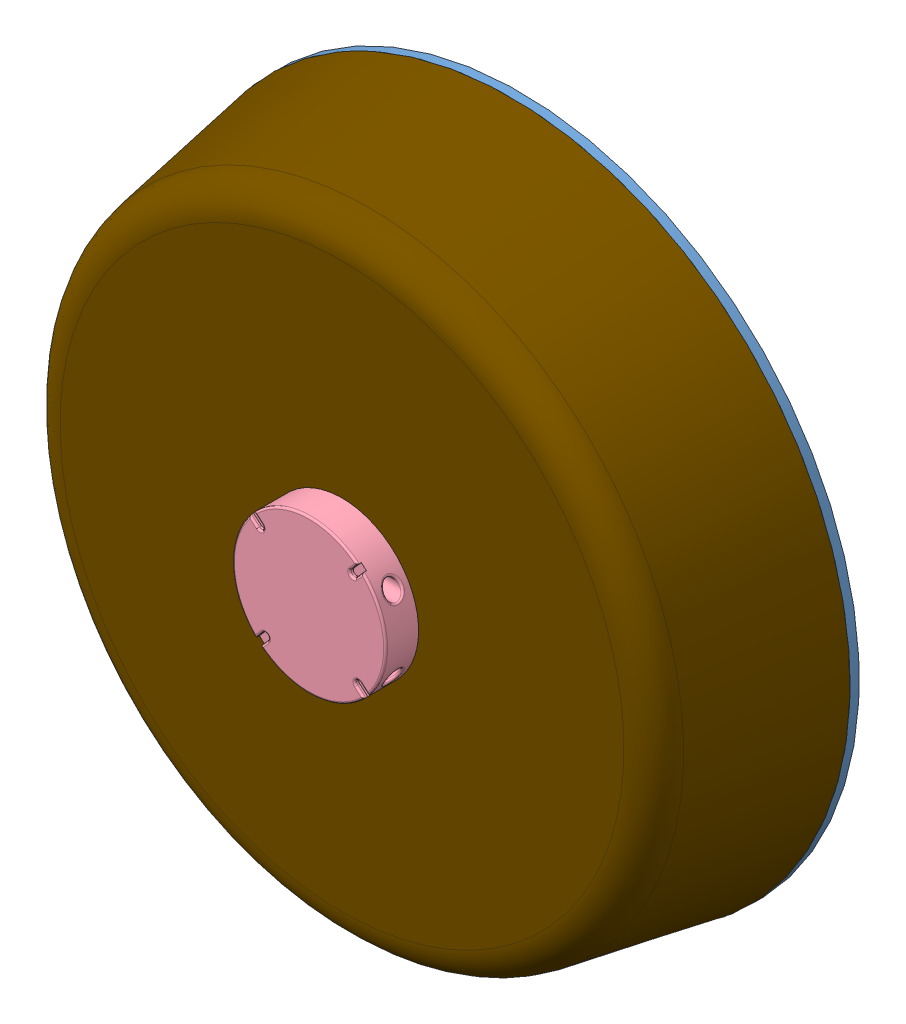
SolidWorks assembly Assembly, configuration Default. Lengths in mm.
Overall size (471.24 471.24 136.97).
49 component instances, 23 part files, 116 mates.
Components (placement in the parent):
- base 4.75mm MDF-1: base 4.75mm MDF [Default] at (205.0733 190.9358 207.8318) size (350 350 4.75)
- caster rise-1: caster rise [Default] at (335.0733 220.9358 207.8318) x (-1 0 0) z (0 1 0) size (60 32 4.75)
- caster rise-2: caster rise [Default] at (275.0733 160.9358 207.8318) x (1 0 0) z (0 -1 0) size (60 32 4.75)
- caster attatchment plate-1: caster attatchment plate [Default] at (305.0733 190.9358 230.0818) size (60 69.5 4.75)
- motor side mdf-1: motor side mdf [Default] at (270.0733 296.9358 212.5818) x (-1 0 0) z (0 1 0) size (115.32 83 4.75)
- motor side mdf-2: motor side mdf [Default] at (270.0733 80.1858 212.5818) x (-1 0 0) z (0 1 0) size (115.32 83 4.75)
- outside side mdf-1: outside side mdf [Default] at (270.0733 330.9358 212.5818) x (-1 0 0) z (0 1 0) size (115.32 83 4.75)
- inside side base-3: inside side base [Default] at (165.0733 330.9358 212.5818) size (95 23 4.75)
- inside side base-4: inside side base [Default] at (165.0733 50.9358 217.3318) x (1 0 0) z (0 0 -1) size (95 23 4.75)
- outside side mdf-2: outside side mdf [Default] at (270.0733 46.1858 212.5818) x (-1 0 0) z (0 1 0) size (115.32 83 4.75)
- wheel cover-1: wheel cover [Default] at (285.0733 330.9358 212.5818) x (-1 0 0) z (0 1 0) size (119.84 83 29.25)
- wheel cover-2: wheel cover [Default] at (285.0733 80.1858 212.5818) x (-1 0 0) z (0 1 0) size (119.84 83 29.25)
- Arm mdf model-1: Arm mdf model [Default] at (210.848 314.4358 240.6942) x (0.799121 0 -0.60117) z (0 -1 0) size (25 92.5 36.95)
- Arm mdf model-2: Arm mdf model [Default] at (218.8392 69.2358 234.6825) x (-0.799121 0 0.60117) z (0 1 0) size (25 92.5 36.95)
- wheel-1: wheel [Default] at (207.9564 56.4358 228.5333) x (0.99189 0 0.127103) z (0 1 0) size (70 70 9)
- wheel-2: wheel [Default] at (207.9564 325.4358 228.5333) x (-0.581743 0 0.813373) z (0 -1 0) size (70 70 9)
- 3mm pin cavity-2: 3mm pin cavity [Default] at (277.411 65.5608 197.5818) size (3 3 20) (hidden)
- 3mm pin cavity-4: 3mm pin cavity [Default] at (277.411 316.3108 197.5818) size (3 3 20) (hidden)
- arm rod block-1: arm rod block [Default] at (225.5649 41.4358 277.495) x (1 0 0) z (0 1 0) size (15 15 4.75)
- arm rod block-2: arm rod block [Default] at (183.4988 89.6858 262.2969) x (1 0 0) z (0 -1 0) size (15 15 4.75)
- arm rod block-3: arm rod block [Default] at (228.2215 292.1858 278.3933) x (1 0 0) z (0 1 0) size (15 15 4.75)
- arm rod block-4: arm rod block [Default] at (229.3289 340.4358 265.9607) x (1 0 0) z (0 -1 0) size (15 15 4.75)
- motor side supports mdf-5: motor side supports mdf [Default] at (169.8233 296.9358 217.3318) x (0 -1 0) z (-1 0 0) size (23 24.75 4.75)
- motor side supports mdf-6: motor side supports mdf [Default] at (260.0733 296.9358 217.3318) x (0 -1 0) z (-1 0 0) size (23 24.75 4.75)
- motor side supports mdf-7: motor side supports mdf [Default] at (165.0733 335.6858 217.3318) x (0 1 0) z (1 0 0) size (23 24.75 4.75)
- motor side supports mdf-8: motor side supports mdf [Default] at (255.3233 335.6858 217.3318) x (0 1 0) z (1 0 0) size (23 24.75 4.75)
- inside side base parts-1: inside side base parts [Default] at (260.0733 80.1858 212.5818) x (-1 0 0) z (0 0 1) size (20 23 4.75)
- inside side base parts-3: inside side base parts [Default] at (165.0733 80.1858 217.3318) x (1 0 0) z (0 0 -1) size (20 23 4.75)
- motor side supports mdf-9: motor side supports mdf [Default] at (165.0733 84.9358 217.3318) x (0 1 0) z (1 0 0) size (23 24.75 4.75)
- motor side supports mdf-10: motor side supports mdf [Default] at (255.3233 84.9358 217.3318) x (0 1 0) z (1 0 0) size (23 24.75 4.75)
- motor side supports mdf-11: motor side supports mdf [Default] at (169.8233 46.1858 217.3318) x (0 -1 0) z (-1 0 0) size (23 24.75 4.75)
- motor side supports mdf-12: motor side supports mdf [Default] at (260.0733 46.1858 217.3318) x (0 -1 0) z (-1 0 0) size (23 24.75 4.75)
- inside side base parts-4: inside side base parts [Default] at (260.0733 301.6858 217.3318) x (-1 0 0) z (0 0 -1) size (20 23 4.75)
- inside side base parts-5: inside side base parts [Default] at (165.0733 301.6858 212.5818) size (20 23 4.75)
- 3mm pin cavity-5: 3mm pin cavity [Default] at (261.6585 38.9358 265.4258) x (1 0 0) z (0 1 0) size (3 3 20) (hidden)
- 3mm pin cavity-6: 3mm pin cavity [Default] at (261.6585 70.2183 265.4258) x (0.998958 0 -0.04563) z (0 1 0) size (3 3 20) (hidden)
- 25d-metal-gearmotor-75-99-encoder.step-1: 25d-metal-gearmotor-75-99-encoder.step [Default] at (207.9564 70.8358 228.5333) x (-0.811037 0 -0.584995) z (0 -1 0) size (25 30.75 80.95)
- 25d-metal-gearmotor-75-99-encoder.step-2: 25d-metal-gearmotor-75-99-encoder.step [Default] at (207.9564 312.8358 228.5333) x (0.533758 0 -0.845638) z (0 1 0) size (25 30.75 80.95)
- distance sensor-1: distance sensor [Default] at (370.0733 213.4358 222.1818) x (0 -1 0) z (1 0 0) size (45 15.6 20)
- vacuum area-1: vacuum area [Default] at (247.5733 190.9358 232.5818) x (0 1 0) z (0 0 -1) size (209.33 123.21 63.23)
- Battery holder v2-1: Battery holder v2 [Default] at (157.4034 248.4358 231.5818) x (0 -1 0) z (0 0 -1) size (125 51 24)
- dust bin-1: dust bin [Default] at (210.0733 190.9358 212.5818) x (0 0 1) z (0 1 0) size (86.03 115 321.71)
- case-1: case [Default] at (205.0733 190.9358 212.5818) x (-0.889778 -0.456394 0) z (-0.456394 0.889778 0) size (350.06 87 350.06)
- caster-1: caster [Default] at (305.0733 190.9358 230.0818) x (-1 0 0) z (0 0 -1) size (40 30 35.5)
- spring-1: spring [Default] at (183.9288 70.7358 291.8887) x (0.049441 0 0.998777) z (0 1 0) size (6.1 79.2 5.8)
- spring-2: spring [Default] at (243.8514 312.9358 288.8336) x (0.03981 0 0.999207) z (0 -1 0) size (6.1 79.2 5.8)
- XV11-main-1: XV11-main [Default] at (195.3613 245.7963 277.4612) x (0 1 0) z (1 0 0) size (99.25 29.09 118.97)
  - base-plate-1: base-plate [Default] at (-54.8605 13.6206 9.712) size (99.25 7 118.97)
  - revolving-body-1: revolving-body [Default] at (-54.8605 20.1206 9.712) size (84.29 22.09 84.29)
Mates (geometry in assembly coordinates):
- Coincident1: coincident anti-aligned: plane of base 4.75mm MDF-1 through (205.0733 190.9358 212.5818) normal (0 0 1); plane of caster rise-2 through (285.0733 156.1858 212.5818) normal (0 0 -1)
- Coincident2: coincident aligned: plane of base 4.75mm MDF-1 through (335.0733 160.9358 212.5818) normal (0 1 0); plane of caster rise-2 through (275.0733 160.9358 207.8318) normal (0 1 0)
- Coincident3: coincident anti-aligned: plane of base 4.75mm MDF-1 through (335.0733 220.9358 212.5818) normal (-1 0 0); plane of caster rise-2 through (335.0733 156.1858 207.8318) normal (1 0 0)
- Coincident7: coincident aligned: plane of caster rise-2 through (275.0733 156.1858 207.8318) normal (0 -1 0); plane of caster attatchment plate-1 through (275.0733 156.1858 234.8318) normal (0 -1 0)
- Coincident8: coincident aligned: plane of caster rise-2 through (335.0733 156.1858 207.8318) normal (1 0 0); plane of caster attatchment plate-1 through (335.0733 156.1858 234.8318) normal (1 0 0)
- Coincident20: coincident aligned: plane of outside side mdf-1 through (236.512 330.9358 266.4915) normal (0 -1 0); plane of inside side base-3 through (165.0733 330.9358 217.3318) normal (0 -1 0)
- Coincident21: coincident aligned: plane of outside side mdf-1 through (165.0733 335.6858 212.5818) normal (0 0 -1); plane of inside side base-3 through (165.0733 330.9358 212.5818) normal (0 0 -1)
- Coincident22: coincident aligned: plane of outside side mdf-1 through (165.0733 335.6858 295.5818) normal (-1 0 0); plane of inside side base-3 through (165.0733 330.9358 217.3318) normal (-1 0 0)
- Coincident23: coincident anti-aligned: plane of base 4.75mm MDF-1 through (205.0733 190.9358 212.5818) normal (0 0 1); plane of inside side base-3 through (165.0733 330.9358 212.5818) normal (0 0 -1)
- Coincident24: coincident anti-aligned: line of base 4.75mm MDF-1 through (165.0733 330.9358 212.5818) axis (1 0 0); line of outside side mdf-1 through (207.5733 330.9358 212.5818) axis (-1 0 0)
- Coincident26: coincident anti-aligned: line of base 4.75mm MDF-1 through (165.0733 310.9358 212.5818) axis (0 1 0); line of inside side base-3 through (165.0733 348.9358 212.5818) axis (0 -1 0)
- Coincident27: coincident anti-aligned: plane of inside side base-4 through (175.0733 46.1858 217.3318) normal (0 1 0); plane of outside side mdf-2 through (236.512 46.1858 266.4915) normal (0 -1 0)
- Coincident28: coincident anti-aligned: plane of inside side base-4 through (165.0733 50.9358 217.3318) normal (0 0 1); plane of outside side mdf-2 through (260.0733 46.1858 217.3318) normal (0 0 -1)
- Coincident29: coincident aligned: plane of inside side base-4 through (165.0733 50.9358 212.5818) normal (-1 0 0); plane of outside side mdf-2 through (165.0733 50.9358 295.5818) normal (-1 0 0)
- Coincident31: coincident anti-aligned: plane of base 4.75mm MDF-1 through (205.0733 190.9358 212.5818) normal (0 0 1); plane of inside side base-4 through (165.0733 50.9358 212.5818) normal (0 0 -1)
- Coincident32: coincident aligned: plane of motor side mdf-2 through (165.0733 84.9358 295.5818) normal (-1 0 0); plane of outside side mdf-2 through (165.0733 50.9358 295.5818) normal (-1 0 0)
- Coincident33: coincident aligned: plane of base 4.75mm MDF-1 through (245.0733 50.9358 212.5818) normal (0 1 0); plane of outside side mdf-2 through (236.512 50.9358 266.4915) normal (0 1 0)
- Coincident34: coincident anti-aligned: plane of base 4.75mm MDF-1 through (165.0733 70.9358 212.5818) normal (1 0 0); plane of inside side base-4 through (165.0733 50.9358 212.5818) normal (-1 0 0)
- Parallel3: parallel anti-aligned: plane of motor side mdf-1 through (236.512 301.6858 266.4915) normal (0 1 0); plane of outside side mdf-1 through (236.512 330.9358 266.4915) normal (0 -1 0)
- Parallel4: parallel anti-aligned: plane of motor side mdf-2 through (236.512 80.1858 266.4915) normal (0 -1 0); plane of outside side mdf-2 through (236.512 50.9358 266.4915) normal (0 1 0)
- Coincident37: coincident aligned: plane of motor side mdf-1 through (165.0733 301.6858 295.5818) normal (-1 0 0); plane of outside side mdf-1 through (165.0733 335.6858 295.5818) normal (-1 0 0)
- Distance2: distance = 29.25 mm anti-aligned: plane of motor side mdf-2 through (236.512 80.1858 266.4915) normal (0 -1 0); plane of outside side mdf-2 through (236.512 50.9358 266.4915) normal (0 1 0)
- Coincident40: coincident anti-aligned: plane of base 4.75mm MDF-1 through (205.0733 190.9358 212.5818) normal (0 0 1); plane of wheel cover-1 through (285.0733 335.9358 212.5818) normal (0 0 -1)
- Coincident41: coincident aligned: plane of outside side mdf-1 through (165.0733 335.6858 295.5818) normal (-1 0 0); plane of wheel cover-1 through (165.0733 335.9358 212.5818) normal (-1 0 0)
- Coincident42: coincident anti-aligned: plane of outside side mdf-1 through (236.512 330.9358 266.4915) normal (0 -1 0); plane of wheel cover-1 through (285.0733 330.9358 212.5818) normal (0 1 0)
- Coincident43: coincident anti-aligned: plane of base 4.75mm MDF-1 through (205.0733 190.9358 212.5818) normal (0 0 1); plane of wheel cover-2 through (285.0733 85.1858 212.5818) normal (0 0 -1)
- Coincident44: coincident aligned: plane of motor side mdf-2 through (165.0733 84.9358 295.5818) normal (-1 0 0); plane of wheel cover-2 through (165.0733 85.1858 212.5818) normal (-1 0 0)
- Coincident45: coincident anti-aligned: plane of motor side mdf-2 through (236.512 80.1858 266.4915) normal (0 -1 0); plane of wheel cover-2 through (285.0733 80.1858 212.5818) normal (0 1 0)
- Concentric1: concentric anti-aligned: cylinder of outside side mdf-2 through (236.512 50.9358 266.4915) axis (0 -1 0) radius 2.5; cylinder of Arm mdf model-2 through (236.512 47.9858 266.4915) axis (0 1 0) radius 2.5
- Concentric5: concentric anti-aligned: cylinder of wheel cover-2 through (277.411 65.5608 212.5818) axis (0 0 1) radius 1.5; cylinder of 3mm pin cavity-2 through (277.411 65.5608 217.5818) axis (0 0 -1) radius 1.5
- Coincident50: coincident aligned: plane of wheel cover-2 through (264.911 85.1858 217.5818) normal (0 0 1); plane of 3mm pin cavity-2 through (277.411 65.5608 217.5818) normal (0 0 1)
- Concentric6: concentric anti-aligned: cylinder of wheel cover-1 through (277.411 316.3108 212.5818) axis (0 0 1) radius 1.5; cylinder of 3mm pin cavity-4 through (277.411 316.3108 217.5818) axis (0 0 -1) radius 1.5
- Coincident52: coincident aligned: plane of wheel cover-1 through (264.911 335.9358 217.5818) normal (0 0 1); plane of 3mm pin cavity-4 through (277.411 316.3108 217.5818) normal (0 0 1)
- Concentric9: concentric anti-aligned: cylinder of motor side mdf-1 through (236.512 301.6858 266.4915) axis (0 -1 0) radius 2.5; cylinder of Arm mdf model-1 through (236.512 298.7358 266.4915) axis (0 1 0) radius 2.5
- Coincident57: coincident anti-aligned: plane of caster rise-2 through (285.0733 156.1858 230.0818) normal (0 0 1); plane of caster attatchment plate-1 through (305.0733 190.9358 230.0818) normal (0 0 -1)
- Coincident58: coincident aligned: plane of base 4.75mm MDF-1 through (205.0733 190.9358 207.8318) normal (0 0 -1); plane of caster rise-1 through (285.0733 225.6858 207.8318) normal (0 0 -1)
- Coincident59: coincident aligned: plane of base 4.75mm MDF-1 through (335.0733 220.9358 212.5818) normal (0 -1 0); plane of caster rise-1 through (335.0733 220.9358 207.8318) normal (0 -1 0)
- Coincident60: coincident aligned: plane of caster rise-1 through (335.0733 225.6858 207.8318) normal (1 0 0); plane of caster attatchment plate-1 through (335.0733 156.1858 234.8318) normal (1 0 0)
- Coincident78: coincident anti-aligned: plane of motor side mdf-2 through (236.512 84.9358 266.4915) normal (0 1 0); plane of arm rod block-2 through (183.4988 84.9358 262.2969) normal (0 -1 0)
- Coincident80: coincident anti-aligned: plane of motor side mdf-1 through (236.512 296.9358 266.4915) normal (0 -1 0); plane of arm rod block-3 through (228.2215 296.9358 278.3933) normal (0 1 0)
- Coincident81: coincident anti-aligned: plane of outside side mdf-1 through (236.512 335.6858 266.4915) normal (0 1 0); plane of arm rod block-4 through (229.3289 335.6858 265.9607) normal (0 -1 0)
- Coincident91: coincident anti-aligned: plane of motor side mdf-1 through (236.512 296.9358 266.4915) normal (0 -1 0); plane of motor side supports mdf-5 through (165.0733 296.9358 217.3318) normal (0 1 0)
- Coincident93: coincident anti-aligned: plane of motor side mdf-1 through (236.512 296.9358 266.4915) normal (0 -1 0); plane of motor side supports mdf-6 through (255.3233 296.9358 217.3318) normal (0 1 0)
- Coincident95: coincident aligned: plane of motor side mdf-1 through (165.0733 301.6858 295.5818) normal (-1 0 0); plane of motor side supports mdf-5 through (165.0733 296.9358 217.3318) normal (-1 0 0)
- Coincident96: coincident anti-aligned: plane of outside side mdf-1 through (236.512 335.6858 266.4915) normal (0 1 0); plane of motor side supports mdf-7 through (169.8233 335.6858 217.3318) normal (0 -1 0)
- Coincident98: coincident anti-aligned: plane of inside side base-3 through (165.0733 330.9358 217.3318) normal (0 0 1); plane of motor side supports mdf-7 through (169.8233 348.9358 217.3318) normal (0 0 -1)
- Coincident99: coincident anti-aligned: plane of outside side mdf-1 through (236.512 335.6858 266.4915) normal (0 1 0); plane of motor side supports mdf-8 through (260.0733 335.6858 217.3318) normal (0 -1 0)
- Coincident100: coincident anti-aligned: plane of inside side base-3 through (165.0733 330.9358 217.3318) normal (0 0 1); plane of motor side supports mdf-8 through (260.0733 348.9358 217.3318) normal (0 0 -1)
- Distance6: distance = 5.5 mm anti-aligned: plane of wheel-1 through (207.9564 65.4358 228.5333) normal (0 1 0); plane of base 4.75mm MDF-1 through (245.0733 70.9358 212.5818) normal (0 -1 0)
- Distance7: distance = 5.5 mm anti-aligned: plane of outside side mdf-1 through (236.512 330.9358 266.4915) normal (0 -1 0); plane of wheel-2 through (207.9564 325.4358 228.5333) normal (0 1 0)
- Coincident104: coincident anti-aligned: plane of motor side mdf-1 through (236.512 301.6858 266.4915) normal (0 1 0); plane of wheel cover-1 through (236.512 301.6858 266.4915) normal (0 -1 0)
- Coincident105: coincident anti-aligned: plane of motor side mdf-2 through (236.512 84.9358 266.4915) normal (0 1 0); plane of inside side base parts-1 through (255.0733 84.9358 217.3318) normal (0 -1 0)
- Coincident106: coincident anti-aligned: plane of motor side mdf-2 through (260.0733 80.1858 212.5818) normal (-1 0 0); plane of inside side base parts-1 through (260.0733 80.1858 217.3318) normal (1 0 0)
- Coincident107: coincident anti-aligned: plane of base 4.75mm MDF-1 through (205.0733 190.9358 212.5818) normal (0 0 1); plane of inside side base parts-1 through (260.0733 80.1858 212.5818) normal (0 0 -1)
- Coincident111: coincident anti-aligned: plane of motor side mdf-2 through (236.512 84.9358 266.4915) normal (0 1 0); plane of inside side base parts-3 through (170.0733 84.9358 212.5818) normal (0 -1 0)
- Coincident112: coincident anti-aligned: plane of base 4.75mm MDF-1 through (205.0733 190.9358 212.5818) normal (0 0 1); plane of inside side base parts-3 through (165.0733 80.1858 212.5818) normal (0 0 -1)
- Coincident113: coincident aligned: plane of motor side mdf-2 through (165.0733 84.9358 295.5818) normal (-1 0 0); plane of inside side base parts-3 through (165.0733 80.1858 212.5818) normal (-1 0 0)
- Coincident114: coincident aligned: plane of inside side base parts-1 through (255.3233 103.1858 217.3318) normal (0 1 0); plane of motor side supports mdf-10 through (260.0733 103.1858 217.3318) normal (0 1 0)
- Coincident115: coincident anti-aligned: plane of base 4.75mm MDF-1 through (205.0733 190.9358 212.5818) normal (0 0 1); plane of motor side supports mdf-10 through (260.0733 103.1858 212.5818) normal (0 0 -1)
- Coincident116: coincident aligned: plane of inside side base parts-1 through (260.0733 80.1858 217.3318) normal (1 0 0); plane of motor side supports mdf-10 through (260.0733 84.9358 217.3318) normal (1 0 0)
- Coincident117: coincident anti-aligned: plane of motor side mdf-2 through (169.8233 80.1858 227.3318) normal (-1 0 0); plane of motor side supports mdf-9 through (169.8233 84.9358 217.3318) normal (1 0 0)
- Coincident118: coincident anti-aligned: plane of base 4.75mm MDF-1 through (205.0733 190.9358 212.5818) normal (0 0 1); plane of motor side supports mdf-9 through (169.8233 103.1858 212.5818) normal (0 0 -1)
- Coincident119: coincident aligned: plane of motor side mdf-2 through (236.512 80.1858 266.4915) normal (0 -1 0); plane of motor side supports mdf-9 through (169.8233 80.1858 237.3318) normal (0 -1 0)
- Coincident120: coincident aligned: plane of outside side mdf-2 through (236.512 50.9358 266.4915) normal (0 1 0); plane of motor side supports mdf-11 through (165.0733 50.9358 237.3318) normal (0 1 0)
- Coincident121: coincident aligned: plane of outside side mdf-2 through (165.0733 50.9358 295.5818) normal (-1 0 0); plane of motor side supports mdf-11 through (165.0733 46.1858 217.3318) normal (-1 0 0)
- Coincident123: coincident anti-aligned: plane of inside side base-4 through (165.0733 50.9358 217.3318) normal (0 0 1); plane of motor side supports mdf-11 through (165.0733 32.9358 217.3318) normal (0 0 -1)
- Coincident124: coincident anti-aligned: plane of inside side base-4 through (260.0733 32.9358 217.3318) normal (0 -1 0); plane of motor side supports mdf-12 through (255.3233 32.9358 217.3318) normal (0 1 0)
- Coincident125: coincident anti-aligned: plane of inside side base-4 through (255.3233 27.9358 217.3318) normal (1 0 0); plane of motor side supports mdf-12 through (255.3233 46.1858 217.3318) normal (-1 0 0)
- Coincident126: coincident anti-aligned: plane of base 4.75mm MDF-1 through (205.0733 190.9358 212.5818) normal (0 0 1); plane of motor side supports mdf-12 through (255.3233 27.9358 212.5818) normal (0 0 -1)
- Coincident127: coincident anti-aligned: plane of base 4.75mm MDF-1 through (205.0733 190.9358 212.5818) normal (0 0 1); plane of inside side base parts-4 through (260.0733 301.6858 212.5818) normal (0 0 -1)
- Coincident128: coincident anti-aligned: plane of motor side mdf-1 through (260.0733 296.9358 212.5818) normal (-1 0 0); plane of inside side base parts-4 through (260.0733 301.6858 212.5818) normal (1 0 0)
- Coincident129: coincident aligned: plane of motor side mdf-1 through (236.512 301.6858 266.4915) normal (0 1 0); plane of inside side base parts-4 through (245.0733 301.6858 212.5818) normal (0 1 0)
- Coincident130: coincident aligned: plane of motor side supports mdf-6 through (260.0733 296.9358 217.3318) normal (1 0 0); plane of inside side base parts-4 through (260.0733 301.6858 212.5818) normal (1 0 0)
- Coincident131: coincident: line of motor side supports mdf-6 through (260.0733 296.9358 217.3318) axis (0 -1 0); plane of inside side base parts-4 through (260.0733 301.6858 217.3318) normal (0 0 1)
- Coincident132: coincident aligned: plane of motor side mdf-1 through (165.0733 301.6858 295.5818) normal (-1 0 0); plane of inside side base parts-5 through (165.0733 301.6858 217.3318) normal (-1 0 0)
- Coincident133: coincident anti-aligned: plane of base 4.75mm MDF-1 through (205.0733 190.9358 212.5818) normal (0 0 1); plane of inside side base parts-5 through (165.0733 301.6858 212.5818) normal (0 0 -1)
- Coincident134: coincident: line of motor side mdf-1 through (165.0733 301.6858 217.3318) axis (0 0 1); plane of inside side base parts-5 through (165.0733 301.6858 217.3318) normal (0 1 0)
- Coincident135: coincident anti-aligned: plane of motor side supports mdf-5 through (165.0733 283.6858 217.3318) normal (0 0 -1); plane of inside side base parts-5 through (165.0733 301.6858 217.3318) normal (0 0 1)
- Coincident136: coincident aligned: plane of inside side base-3 through (260.0733 330.9358 217.3318) normal (1 0 0); plane of motor side supports mdf-8 through (260.0733 335.6858 217.3318) normal (1 0 0)
- Coincident137: coincident aligned: plane of inside side base-3 through (165.0733 330.9358 217.3318) normal (-1 0 0); plane of motor side supports mdf-7 through (165.0733 335.6858 217.3318) normal (-1 0 0)
- Concentric16: concentric anti-aligned: cylinder of wheel cover-2 through (261.6585 50.9358 265.4258) axis (0 1 0) radius 1.5; cylinder of 3mm pin cavity-5 through (261.6585 58.9358 265.4258) axis (0 -1 0) radius 1.5
- Concentric17: concentric anti-aligned: cylinder of wheel cover-2 through (261.6585 50.9358 265.4258) axis (0 1 0) radius 1.5; cylinder of 3mm pin cavity-6 through (261.6585 90.2183 265.4258) axis (0 -1 0) radius 1.5
- Concentric19: concentric aligned: cylinder of Arm mdf model-2 through (207.9564 70.8358 228.5333) axis (0 -1 0) radius 1.5; cylinder of 25d-metal-gearmotor-75-99-encoder.step-1 through (207.9564 70.8358 228.5333) axis (0 -1 0) radius 2
- Coincident138: coincident anti-aligned: plane of Arm mdf model-2 through (207.9564 70.8358 228.5333) normal (0 1 0); plane of 25d-metal-gearmotor-75-99-encoder.step-1 through (207.9564 70.8358 228.5333) normal (0 -1 0)
- Concentric20: concentric aligned: cylinder of Arm mdf model-1 through (207.9564 312.8358 228.5333) axis (0 1 0) radius 1.5; cylinder of 25d-metal-gearmotor-75-99-encoder.step-2 through (207.9564 312.8358 228.5333) axis (0 1 0) radius 2
- Coincident139: coincident aligned: plane of motor side mdf-1 through (236.512 301.6858 295.5818) normal (0 0 1); plane of wheel cover-1 through (285.0733 330.9358 295.5818) normal (0 0 1)
- Coincident140: coincident anti-aligned: plane of Arm mdf model-1 through (207.9564 312.8358 228.5333) normal (0 -1 0); plane of 25d-metal-gearmotor-75-99-encoder.step-2 through (207.9564 312.8358 228.5333) normal (0 1 0)
- Concentric21: concentric aligned: cylinder of base 4.75mm MDF-1 through (360.0733 178.4358 207.8318) axis (0 0 1) radius 8.5; cylinder of distance sensor-1 through (360.0733 178.4358 206.5818) axis (0 0 1) radius 8
- Concentric22: concentric aligned: cylinder of base 4.75mm MDF-1 through (360.0733 203.4358 207.8318) axis (0 0 1) radius 8.5; cylinder of distance sensor-1 through (360.0733 203.4358 206.5818) axis (0 0 1) radius 8
- Distance8: distance = 8 mm anti-aligned: plane of distance sensor-1 through (370.0733 213.4358 220.5818) normal (0 0 -1); plane of base 4.75mm MDF-1 through (205.0733 190.9358 212.5818) normal (0 0 1)
- Concentric23: concentric anti-aligned: cylinder of wheel-2 through (207.9564 325.4358 228.5333) axis (0 -1 0) radius 2; cylinder of 25d-metal-gearmotor-75-99-encoder.step-2 through (207.9564 312.8358 228.5333) axis (0 1 0) radius 2
- Concentric24: concentric anti-aligned: cylinder of wheel-1 through (207.9564 56.4358 228.5333) axis (0 1 0) radius 2; cylinder of 25d-metal-gearmotor-75-99-encoder.step-1 through (207.9564 70.8358 228.5333) axis (0 -1 0) radius 2
- Coincident145: coincident aligned: plane of outside side mdf-1 through (236.512 335.6858 266.4915) normal (0 1 0); plane of Arm mdf model-1 through (236.512 335.6858 266.4915) normal (0 1 0)
- Coincident146: coincident aligned: plane of motor side mdf-2 through (236.512 84.9358 266.4915) normal (0 1 0); plane of Arm mdf model-2 through (236.512 84.9358 266.4915) normal (0 1 0)
- Concentric25: concentric anti-aligned: circle of wheel-1; circle of wheel-2
- Coincident149: coincident anti-aligned: plane of base 4.75mm MDF-1 through (205.0733 190.9358 212.5818) normal (0 0 1); plane of Battery holder v2-1 through (157.4034 248.4358 212.5818) normal (0 0 -1)
- Coincident151: coincident anti-aligned: plane of base 4.75mm MDF-1 through (205.0733 190.9358 212.5818) normal (0 0 1); plane of vacuum area-1 through (247.5733 190.9358 212.5818) normal (0 0 -1)
- Coincident152: coincident: point of base 4.75mm MDF-1; point of vacuum area-1
- Coincident153: coincident anti-aligned: line of base 4.75mm MDF-1 through (265.0733 110.9358 212.5818) axis (0 1 0); line of vacuum area-1 through (265.0733 270.9358 212.5818) axis (0 -1 0)
- Parallel6: parallel aligned: line of vacuum area-1 through (155.0733 150.9358 242.5818) axis (0 1 0); line of Battery holder v2-1 through (121.4034 128.4358 236.5818) axis (0 1 0)
- Coincident155: coincident anti-aligned: plane of base 4.75mm MDF-1 through (205.0733 190.9358 212.5818) normal (0 0 1); plane of dust bin-1 through (210.0733 190.9358 212.5818) normal (0 0 -1)
- Coincident158: coincident anti-aligned: plane of Battery holder v2-1 through (157.4034 128.4358 212.5818) normal (0 -1 0); plane of dust bin-1 through (139.0733 128.4358 212.5818) normal (0 1 0)
- Coincident159: coincident anti-aligned: plane of vacuum area-1 through (155.0733 190.9358 232.5818) normal (-1 0 0); plane of dust bin-1 through (155.0733 351.7929 297.5818) normal (1 0 0)
- Coincident160: coincident aligned: line of vacuum area-1 through (155.0733 230.9358 242.5818) axis (0 0 1); line of dust bin-1 through (155.0733 230.9358 242.5818) axis (0 0 1)
- Concentric26: concentric aligned: circle of base 4.75mm MDF-1; circle of case-1
- Coincident161: coincident anti-aligned: plane of base 4.75mm MDF-1 through (205.0733 190.9358 212.5818) normal (0 0 1); plane of case-1 through (205.0733 190.9358 212.5818) normal (0 0 -1)
- Coincident163: coincident anti-aligned: plane of caster attatchment plate-1 through (305.0733 190.9358 230.0818) normal (0 0 -1); plane of caster-1 through (305.0733 190.9358 230.0818) normal (0 0 1)
- Concentric29: concentric anti-aligned: cylinder of caster attatchment plate-1 through (320.0733 178.9358 230.0818) axis (0 0 1) radius 1.5; cylinder of caster-1 through (320.0733 178.9358 230.0818) axis (0 0 -1) radius 1.5
- Concentric30: concentric anti-aligned: cylinder of caster attatchment plate-1 through (320.0733 202.9358 230.0818) axis (0 0 1) radius 1.5; cylinder of caster-1 through (320.0733 202.9358 230.0818) axis (0 0 -1) radius 1.5
- Concentric32: concentric anti-aligned: cylinder of Arm mdf model-2 through (253.0441 69.2358 288.4674) axis (0 1 0) radius 1.5; cylinder of spring-1 through (253.0441 73.6358 288.4674) axis (0 -1 0) radius 0.4
- Distance9: distance = 2 mm: line of spring-1 through (243.8554 72.8358 288.9222) axis (0.998777 0 -0.049441); plane of Arm mdf model-2 through (207.9564 70.8358 228.5333) normal (0 1 0)
- Concentric33: concentric aligned: cylinder of Arm mdf model-1 through (253.0441 314.4358 288.4674) axis (0 -1 0) radius 1.5; cylinder of spring-2 through (253.0441 312.9358 288.4674) axis (0 -1 0) radius 0.4
- Distance11: distance = 2 mm: line of spring-2 through (252.6445 310.8358 288.4833) axis (-0.999207 0 0.03981); plane of Arm mdf model-1 through (207.9564 312.8358 228.5333) normal (0 -1 0)
- Parallel9: parallel anti-aligned: line of motor side mdf-2 through (217.8233 84.9358 295.5818) axis (1 0 0); line of XV11-main-1/base-plate-1 through (271.9571 190.9358 294.5818) axis (-1 0 0)
- Concentric35: concentric anti-aligned: cylinder of case-1 through (205.0733 190.9358 289.5818) axis (0 0 1) radius 39.5; cylinder of XV11-main-1/revolving-body-1 through (205.0733 190.9358 316.5818) axis (0 0 -1) radius 39.5
- Coincident169: coincident aligned: circle of case-1; circle of XV11-main-1/revolving-body-1
